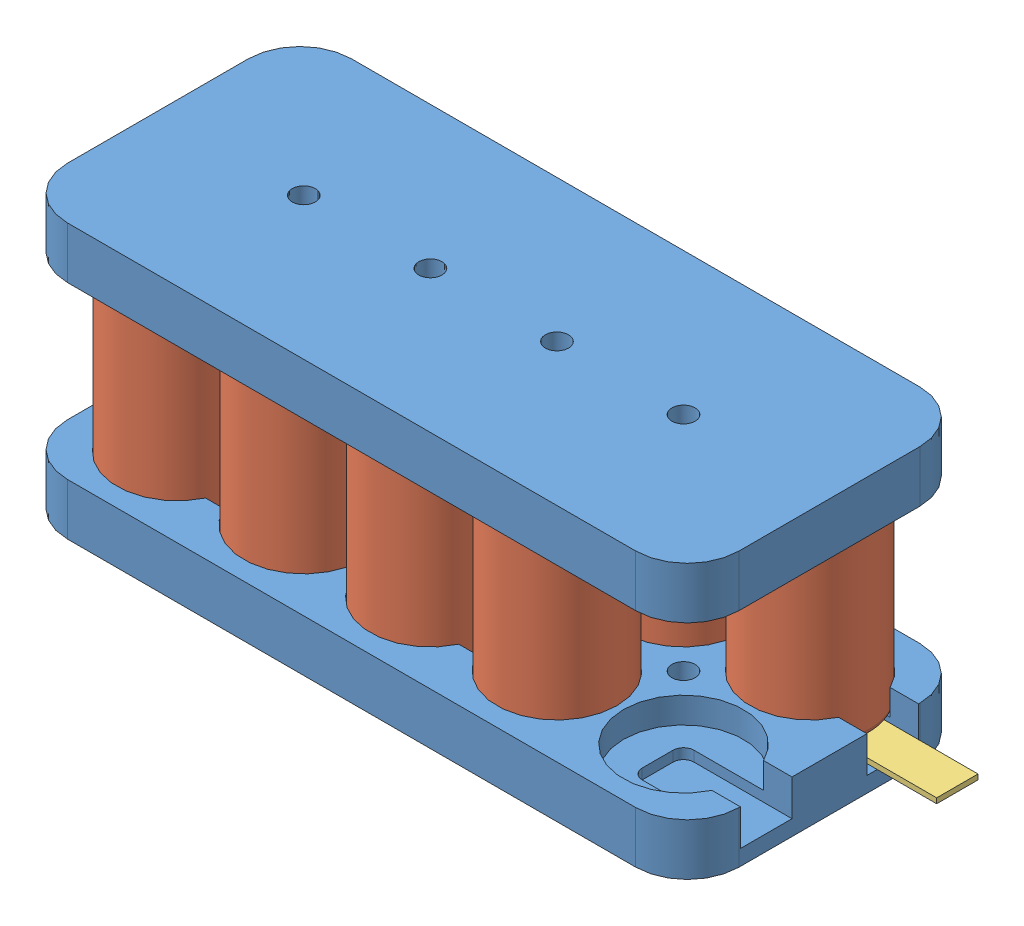
SolidWorks assembly Battery_Pack_9Zellen, configuration Standard. Lengths in mm.
Overall size (142.5 53 55).
21 component instances, 3 part files, 40 mates.
Components (placement in the parent):
- Zellenhalterung-1: Zellenhalterung [Unten] at origin size (130 10 55)
- BK300SCP_Zelle-1: BK300SCP_Zelle [Standard] at (16 5 -39.75) x (1 0 0) z (0 -1 0) size (23 23 43)
- BK300SCP_Zelle-2: BK300SCP_Zelle [Standard] at (40.5 48 -39.75) x (1 0 0) z (0 1 0) size (23 23 43)
- BK300SCP_Zelle-3: BK300SCP_Zelle [Standard] at (65 5 -39.75) x (1 0 0) z (0 -1 0) size (23 23 43)
- BK300SCP_Zelle-4: BK300SCP_Zelle [Standard] at (89.5 48 -39.75) x (1 0 0) z (0 1 0) size (23 23 43)
- BK300SCP_Zelle-5: BK300SCP_Zelle [Standard] at (114 5 -39.75) x (1 0 0) z (0 -1 0) size (23 23 43)
- BK300SCP_Zelle-6: BK300SCP_Zelle [Standard] at (16 48 -15.25) x (1 0 0) z (0 1 0) size (23 23 43)
- BK300SCP_Zelle-7: BK300SCP_Zelle [Standard] at (40.5 5 -15.25) x (1 0 0) z (0 -1 0) size (23 23 43)
- BK300SCP_Zelle-8: BK300SCP_Zelle [Standard] at (65 48 -15.25) x (-1 0 0) z (0 1 0) size (23 23 43)
- BK300SCP_Zelle-9: BK300SCP_Zelle [Standard] at (89.5 5 -15.25) x (1 0 0) z (0 -1 0) size (23 23 43)
- Zellenhalterung-2: Zellenhalterung [Oben] at (0 53 -55) x (1 0 0) z (0 0 -1) size (130 10 55)
- Zellenverbinder-1: Zellenverbinder [Standard] at (110 5 -43.75) x (1 0 0) z (0 0 -1) size (32.5 1 8)
- Zellenverbinder-2: Zellenverbinder [Standard] at (61 5 -43.75) x (1 0 0) z (0 0 -1) size (32.5 1 8)
- Zellenverbinder-3: Zellenverbinder [Standard] at (12 5 -43.75) x (1 0 0) z (0 0 -1) size (32.5 1 8)
- Zellenverbinder-4: Zellenverbinder [Standard] at (61 5 -19.25) x (1 0 0) z (0 0 -1) size (32.5 1 8)
- Zellenverbinder-5: Zellenverbinder [Standard] at (12 5 -19.25) x (1 0 0) z (0 0 -1) size (32.5 1 8)
- Zellenverbinder-6: Zellenverbinder [Standard] at (118 48 -43.75) x (-1 0 0) z (0 0 -1) size (32.5 1 8)
- Zellenverbinder-7: Zellenverbinder [Standard] at (118 48 -19.25) x (-1 0 0) z (0 0 -1) size (32.5 1 8)
- Zellenverbinder-8: Zellenverbinder [Standard] at (69 48 -43.75) x (-1 0 0) z (0 0 -1) size (32.5 1 8)
- Zellenverbinder-9: Zellenverbinder [Standard] at (69 48 -19.25) x (-1 0 0) z (0 0 -1) size (32.5 1 8)
- Zellenverbinder-10: Zellenverbinder [Standard] at (12 48 -43.75) x (0 0 1) z (-1 0 0) size (32.5 1 8)
Mates (geometry in assembly coordinates):
- Deckungsgleich1: coordinate: point of Zellenhalterung-1; point of assembly
- Konzentrisch10: concentric anti-aligned: cylinder of Zellenhalterung-1 through (114 5 -39.75) axis (0 1 0) radius 11.625; cylinder of BK300SCP_Zelle-5 through (114 5 -39.75) axis (0 -1 0) radius 11.5
- Deckungsgleich11: coincident anti-aligned: plane of Zellenhalterung-1 through (114 5 -39.75) normal (0 1 0); plane of BK300SCP_Zelle-5 through (114 5 -39.75) normal (0 -1 0)
- Konzentrisch11: concentric aligned: cylinder of Zellenhalterung-1 through (89.5 5 -39.75) axis (0 1 0) radius 11.625; cylinder of BK300SCP_Zelle-4 through (89.5 48 -39.75) axis (0 1 0) radius 11.5
- Deckungsgleich12: coincident anti-aligned: plane of Zellenhalterung-1 through (89.5 5 -39.75) normal (0 1 0); plane of BK300SCP_Zelle-4 through (89.5 5 -50.25) normal (0 -1 0)
- Konzentrisch12: concentric anti-aligned: cylinder of Zellenhalterung-1 through (65 5 -39.75) axis (0 1 0) radius 11.625; cylinder of BK300SCP_Zelle-3 through (65 5 -39.75) axis (0 -1 0) radius 11.5
- Deckungsgleich13: coincident anti-aligned: plane of Zellenhalterung-1 through (65 5 -39.75) normal (0 1 0); plane of BK300SCP_Zelle-3 through (65 5 -39.75) normal (0 -1 0)
- Konzentrisch13: concentric aligned: cylinder of Zellenhalterung-1 through (40.5 5 -39.75) axis (0 1 0) radius 11.625; cylinder of BK300SCP_Zelle-2 through (40.5 48 -39.75) axis (0 1 0) radius 11.5
- Deckungsgleich14: coincident anti-aligned: plane of Zellenhalterung-1 through (40.5 5 -39.75) normal (0 1 0); plane of BK300SCP_Zelle-2 through (40.5 5 -50.25) normal (0 -1 0)
- Konzentrisch14: concentric anti-aligned: cylinder of Zellenhalterung-1 through (16 5 -39.75) axis (0 1 0) radius 11.625; cylinder of BK300SCP_Zelle-1 through (16 5 -39.75) axis (0 -1 0) radius 11.5
- Deckungsgleich15: coincident anti-aligned: plane of Zellenhalterung-1 through (16 5 -39.75) normal (0 1 0); plane of BK300SCP_Zelle-1 through (16 5 -39.75) normal (0 -1 0)
- Konzentrisch15: concentric aligned: cylinder of Zellenhalterung-1 through (16 5 -15.25) axis (0 1 0) radius 11.625; cylinder of BK300SCP_Zelle-6 through (16 48 -15.25) axis (0 1 0) radius 11.5
- Deckungsgleich16: coincident anti-aligned: plane of Zellenhalterung-1 through (16 5 -15.25) normal (0 1 0); plane of BK300SCP_Zelle-6 through (16 5 -25.75) normal (0 -1 0)
- Konzentrisch16: concentric anti-aligned: cylinder of Zellenhalterung-1 through (40.5 5 -15.25) axis (0 1 0) radius 11.625; cylinder of BK300SCP_Zelle-7 through (40.5 5 -15.25) axis (0 -1 0) radius 11.5
- Deckungsgleich17: coincident anti-aligned: plane of Zellenhalterung-1 through (40.5 5 -15.25) normal (0 1 0); plane of BK300SCP_Zelle-7 through (40.5 5 -15.25) normal (0 -1 0)
- Konzentrisch17: concentric aligned: cylinder of Zellenhalterung-1 through (65 5 -15.25) axis (0 1 0) radius 11.625; cylinder of BK300SCP_Zelle-8 through (65 48 -15.25) axis (0 1 0) radius 11.5
- Deckungsgleich18: coincident anti-aligned: plane of Zellenhalterung-1 through (65 5 -15.25) normal (0 1 0); plane of BK300SCP_Zelle-8 through (65 5 -4.75) normal (0 -1 0)
- Konzentrisch18: concentric anti-aligned: cylinder of Zellenhalterung-1 through (89.5 5 -15.25) axis (0 1 0) radius 11.625; cylinder of BK300SCP_Zelle-9 through (89.5 5 -15.25) axis (0 -1 0) radius 11.5
- Deckungsgleich19: coincident anti-aligned: plane of Zellenhalterung-1 through (89.5 5 -15.25) normal (0 1 0); plane of BK300SCP_Zelle-9 through (89.5 5 -15.25) normal (0 -1 0)
- Parallel1: parallel aligned: plane of Zellenhalterung-1 through (0 0 0) normal (1 0 0); plane of BK300SCP_Zelle-1
- Parallel2: parallel aligned: plane of BK300SCP_Zelle-2; plane of assembly through (0 0 0) normal (1 0 0)
- Parallel3: parallel aligned: plane of BK300SCP_Zelle-3; plane of assembly through (0 0 0) normal (1 0 0)
- Parallel4: parallel aligned: plane of BK300SCP_Zelle-4; plane of assembly through (0 0 0) normal (1 0 0)
- Parallel5: parallel aligned: plane of BK300SCP_Zelle-5; plane of assembly through (0 0 0) normal (1 0 0)
- Parallel6: parallel aligned: plane of BK300SCP_Zelle-6; plane of assembly through (0 0 0) normal (1 0 0)
- Parallel7: parallel aligned: plane of BK300SCP_Zelle-7; plane of assembly through (0 0 0) normal (1 0 0)
- Parallel8: parallel aligned: plane of BK300SCP_Zelle-9; plane of assembly through (0 0 0) normal (1 0 0)
- Parallel9: parallel anti-aligned: plane of BK300SCP_Zelle-8; plane of assembly through (0 0 0) normal (1 0 0)
- Deckungsgleich29: coincident anti-aligned: plane of BK300SCP_Zelle-6 through (16 48 -15.25) normal (0 1 0); plane of Zellenhalterung-2 through (16 48 -15.25) normal (0 -1 0)
- Deckungsgleich30: coincident aligned: plane of Zellenhalterung-1 through (0 10 0) normal (0 0 1); plane of Zellenhalterung-2 through (0 43 0) normal (0 0 1)
- Deckungsgleich31: coincident aligned: plane of Zellenhalterung-1 through (0 10 0) normal (-1 0 0); plane of Zellenhalterung-2 through (0 43 -55) normal (-1 0 0)
- Deckungsgleich32: coincident anti-aligned: plane of BK300SCP_Zelle-5 through (114 5 -39.75) normal (0 -1 0); plane of Zellenverbinder-1 through (110 5 -43.75) normal (0 1 0)
- Konzentrisch19: concentric anti-aligned: circle of BK300SCP_Zelle-5; circle of Zellenverbinder-1
- Parallel10: parallel aligned: plane of Zellenhalterung-1 through (0 10 -55) normal (0 0 -1); plane of Zellenverbinder-1 through (110 4 -43.75) normal (0 0 -1)
- Deckungsgleich34: coincident anti-aligned: plane of BK300SCP_Zelle-5 through (114 48 -35.25) normal (0 1 0); plane of Zellenverbinder-6 through (118 48 -43.75) normal (0 -1 0)
- Konzentrisch20: concentric aligned: circle of BK300SCP_Zelle-5; circle of Zellenverbinder-6
- Parallel11: parallel aligned: plane of Zellenhalterung-2 through (0 43 -55) normal (0 0 -1); plane of Zellenverbinder-6 through (118 49 -43.75) normal (0 0 -1)
- Deckungsgleich36: coincident anti-aligned: plane of BK300SCP_Zelle-1 through (16 48 -35.25) normal (0 1 0); plane of Zellenverbinder-10 through (12 48 -43.75) normal (0 -1 0)
- Konzentrisch21: concentric aligned: circle of BK300SCP_Zelle-1; circle of Zellenverbinder-10
- Parallel12: parallel aligned: plane of Zellenhalterung-2 through (0 43 -55) normal (-1 0 0); plane of Zellenverbinder-10 through (12 49 -43.75) normal (-1 0 0)
